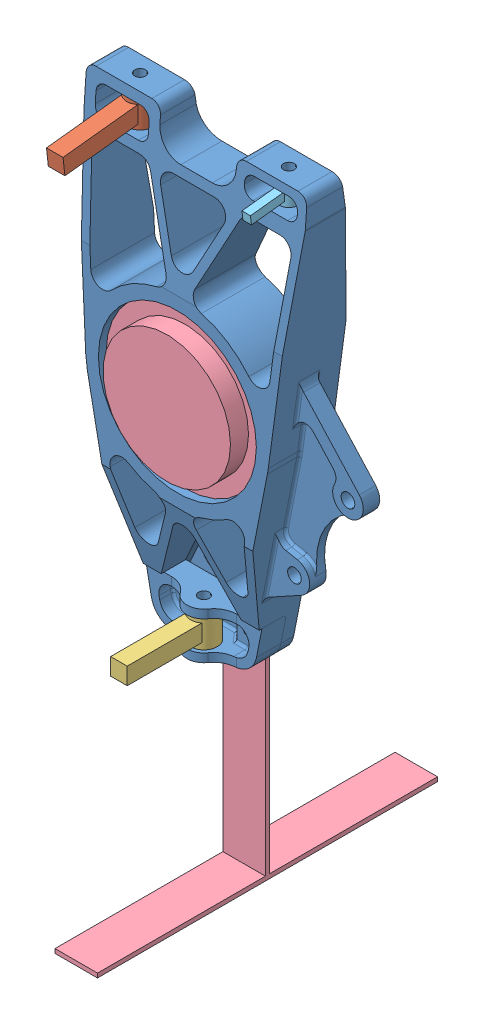
SolidWorks assembly Rear Right Upright Simulation, configuration Default. Lengths in mm.
Overall size (157.48 404.85 203.2).
5 component instances, 5 part files, 12 mates.
Components (placement in the parent):
- Rear Right Upright-1: Rear Right Upright [Default] at (121.1649 172.3469 183.6931) size (157.48 279.03 38.1)
- Upper A-Arm Spherical Joint-1: Upper A-Arm Spherical Joint [Default] at (83.0649 300.4269 186.8681) x (0 0 1) z (-1 0 0) size (58.99 19.46 15.88)
- Lower A-Arm Spherical Joint-1: Lower A-Arm Spherical Joint [Default] at (121.1649 50.4269 186.8681) x (0 0 -1) z (1 0 0) size (58.74 17.6 15.88)
- Hub and Tire-1: Hub and Tire [Default] at (121.1649 172.3469 183.6931) size (93.98 308.61 203.2)
- Toe Link Rod End-1: Toe Link Rod End [Default] at (171.9649 300.4269 186.8681) x (0 0 1) z (-1 0 0) size (31.24 12.06 11.43)
Mates (geometry in assembly coordinates):
- Concentric1: concentric anti-aligned: cylinder of Rear Right Upright-1 through (83.0649 315.578 186.8681) axis (0 -1 0) radius 3.2385; cylinder of Upper A-Arm Spherical Joint-1 through (83.0649 300.4269 186.8681) axis (0 1 0) radius 3.175
- Concentric2: concentric aligned: cylinder of Rear Right Upright-1 through (121.1649 27.3859 186.8681) axis (0 1 0) radius 3.2385; cylinder of Lower A-Arm Spherical Joint-1 through (121.1649 50.4269 186.8681) axis (0 1 0) radius 3.175
- Coincident1: coincident anti-aligned: plane of Rear Right Upright-1 through (67.1899 309.228 164.6431) normal (0 -1 0); plane of Upper A-Arm Spherical Joint-1 through (83.0649 309.228 186.8681) normal (0 1 0)
- Coincident3: coincident anti-aligned: plane of Rear Right Upright-1 through (121.1649 59.228 197.6631) normal (0 -1 0); plane of Lower A-Arm Spherical Joint-1 through (121.1649 59.228 186.8681) normal (0 1 0)
- Parallel1: parallel anti-aligned: plane of Lower A-Arm Spherical Joint-1 through (116.2119 55.5069 186.8681) normal (-1 0 0); plane of assembly through (0 0 0) normal (1 0 0)
- Parallel2: parallel anti-aligned: plane of Upper A-Arm Spherical Joint-1 through (78.1119 295.3779 186.3071) normal (-1 0 0); plane of assembly through (0 0 0) normal (1 0 0)
- Concentric5: concentric aligned: cylinder of Hub and Tire-1 through (121.1649 172.3469 160.2931) axis (0 0 1) radius 38.1; circle of Rear Right Upright-1
- Coincident4: coincident aligned: plane of Rear Right Upright-1 through (121.1649 172.3469 183.6931) normal (0 0 1); plane of Hub and Tire-1 through (121.1649 172.3469 183.6931) normal (0 0 1)
- Parallel4: parallel aligned: plane of Hub and Tire-1 through (121.1649 -86.7331 183.6931) normal (0 1 0); plane of assembly through (0 0 0) normal (0 1 0)
- Coincident5: coincident anti-aligned: plane of Rear Right Upright-1 through (156.0899 306.4594 164.6431) normal (0 -1 0); plane of Toe Link Rod End-1 through (171.9649 306.4594 186.8681) normal (0 1 0)
- Concentric6: concentric anti-aligned: cylinder of Rear Right Upright-1 through (171.9649 315.578 186.8681) axis (0 -1 0) radius 3.2385; cylinder of Toe Link Rod End-1 through (171.9649 294.7119 186.8681) axis (0 1 0) radius 3.175
- Parallel5: parallel anti-aligned: plane of Toe Link Rod End-1 through (169.4249 295.0975 211.8323) normal (-1 0 0); plane of assembly through (0 0 0) normal (1 0 0)
